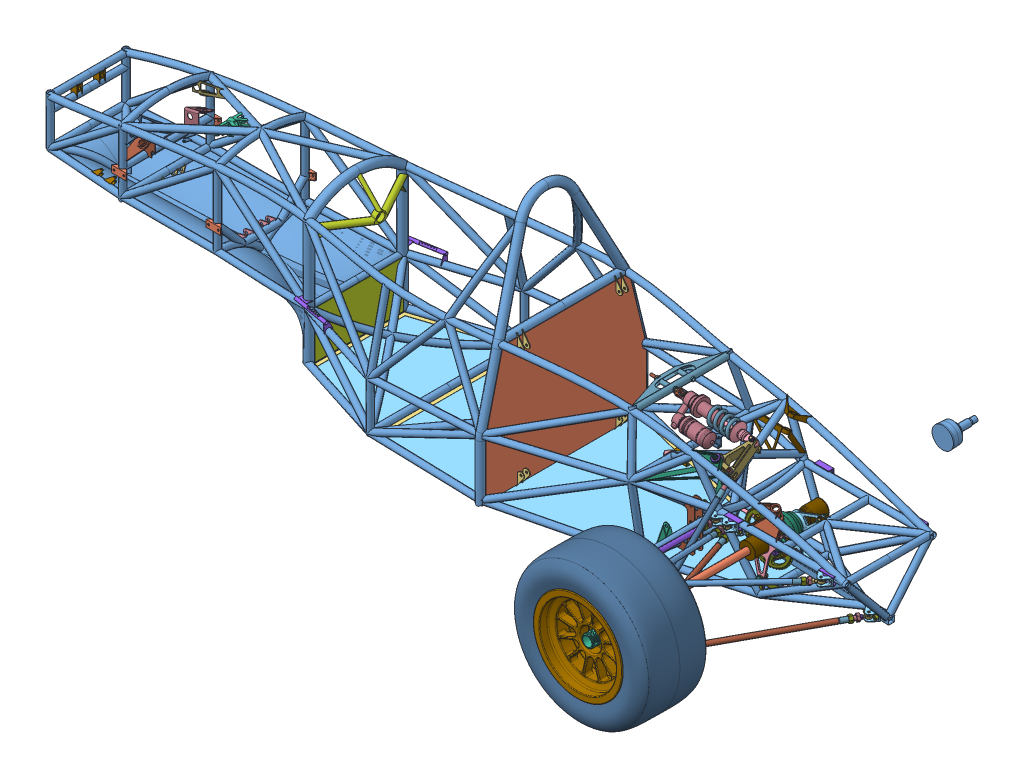
SolidWorks assembly FrameSuspensionRear, configuration Default. Lengths in mm.
Overall size (3537.14 1301.94 1659.72).
268 component instances, 104 part files, 6 mates.
Components (placement in the parent):
- ChassisTop-1: ChassisTop [Default] at origin size (3537.14 1301.94 761.25)
  - Frame-1: Frame [Default<As Machined>] at origin size (3537.14 1301.94 761.25)
  - BracketAarmMountFrontInnerUpper-1: BracketAarmMountFrontInnerUpper [Default] at (-76.9527 359.432 196.9) size (60 28 16.9)
  - BracketAarmMountFrontInnerUpper-2: BracketAarmMountFrontInnerUpper [Default] at (312.8511 359.432 196.9) size (60 28 16.9)
  - BracketAarmMountFrontInnerUpper-3: BracketAarmMountFrontInnerUpper [Default] at (-76.9527 359.432 -196.9) x (-1 0 0) z (0 0 -1) size (60 28 16.9)
  - BracketAarmMountFrontInnerUpper-4: BracketAarmMountFrontInnerUpper [Default] at (312.8511 359.432 -196.9) x (-1 0 0) z (0 0 -1) size (60 28 16.9)
  - BracketPedalMountFront-1: BracketPedalMountFront [Default] at (-76.9527 267.432 -59.5) x (0 0 -1) z (1 0 0) size (3 35 35.55)
  - BracketPedalMountFront-4: BracketPedalMountFront [Default] at (-76.9527 267.432 -28.5) x (0 0 -1) z (1 0 0) size (3 35 35.55)
  - BracketPedalMountFront-5: BracketPedalMountFront [Default] at (-76.9527 267.432 28.5) x (0 0 1) z (-1 0 0) size (3 35 35.55)
  - BracketPedalMountFront-6: BracketPedalMountFront [Default] at (-76.9527 267.432 59.5) x (0 0 1) z (-1 0 0) size (3 35 35.55)
  - BracketPedalMountRear-1: BracketPedalMountRear [Default] at (312.8511 243.432 -61) x (-1 0 0) z (0 0 1) size (41.8 36.23 3)
  - BracketPedalMountRear-2: BracketPedalMountRear [Default] at (312.8511 243.432 -32.3915) x (-1 0 0) z (0 0 1) size (41.8 36.23 3)
  - BracketPedalMountRear-3: BracketPedalMountRear [Default] at (312.8511 243.432 30) x (-1 0 0) z (0 0 1) size (41.8 36.23 3)
  - BracketPedalMountRear-4: BracketPedalMountRear [Default] at (312.8511 243.432 61) x (-0.999488 -0.031993 0) z (0 0 1) size (41.8 36.23 3)
  - BracketSteeringRack-1: BracketSteeringRack [Default] at (-122.845 359.4035 0) x (0 0 1) z (-0.731354 -0.681998 0) size (157.4 28.6 22.45)
  - Part1^ChassisTop-1: Part1^ChassisTop [Default] at origin (virtual)
  - BracketSteeringColumnBearing2-1: BracketSteeringColumnBearing2 [Default<As Machined>] at (1054.5457 325.1906 26.9611) x (0.999998 -0.002043 0.000001) z (0.000001 0.000943 1) size (68.49 50.56 124.92)
  - BracketSteeringColumnBearing3-1: BracketSteeringColumnBearing3 [Default] at (806.6109 544.4207 0) x (0 0 1) z (-0.999391 0.034899 0) size (406.05 183.54 114.99)
  - Road-1: Road [Default] at (899.7928 43.6226 57.1597) (suppressed, hidden)
  - ARB_HandleMountLeft-1: ARB_HandleMountLeft [Default] at (830.0394 301.8025 247.6998) x (-0.985348 0 -0.170553) z (0.170553 0 -0.985348) size (155.3 44.88 41.83)
  - ARB_FrontChassisTabsLeft-1: ARB_FrontChassisTabsLeft [Default<As Machined>] at (-76.9527 267.432 0) x (0 0 1) z (-1 0 0) size (38.22 15.9 83.49)
  - ARB_FrontChassisTabsRight-1: ARB_FrontChassisTabsRight [Default<As Machined>] at (-76.9527 267.432 0) x (0 0 1) z (-1 0 0) size (38.22 15.9 83.49)
  - BracketIdlerSprocket-2: BracketIdlerSprocket [Default] at (2250 187 0) x (0 0 1) z (-1 0 0) size (55.08 192.78 109.89)
    - BracketIdlerSprocket-1: BracketIdlerSprocket [Default<As Machined>] at origin size (36.02 192.78 89.01)
    - B27.7M - 3BM1-28-2: B27.7M - 3BM1-28 [B27.7M - 3BM1-28] at (112.963 9.676 43.223) x (0 0 1) z (-1 0 0) size (29.8 29.16 1.3)
    - ChainTensionerShaft-1: ChainTensionerShaft [Default] at (106.463 9.676 43.223) size (30.8 15 15)
    - Internal Tooth LW Type A-0.375-1: Internal Tooth LW Type A-0.375 [Internal Tooth LW Type A-0.375] at (123.463 9.676 43.223) x (0 -1 0) z (0 0 1) size (17.58 1.02 17.58)
    - Internal Tooth LW Type A-0.375-2: Internal Tooth LW Type A-0.375 [Internal Tooth LW Type A-0.375] at (89.463 9.676 43.223) x (0 1 0) z (0 0 1) size (17.58 1.02 17.58)
    - HX-SHCS 0.375-24x0.5x0.5-S-1: HX-SHCS 0.375-24x0.5x0.5-S [HX-SHCS 0.375-24x0.5x0.5-S] at (78.922 9.676 43.223) size (22.23 14.29 14.29)
    - HX-SHCS 0.375-24x0.5x0.5-S-2: HX-SHCS 0.375-24x0.5x0.5-S [HX-SHCS 0.375-24x0.5x0.5-S] at (134.004 9.676 43.223) x (-1 0 0) z (0 0.924225 0.381849) size (22.23 14.29 14.29)
    - B27.7M - 3BM1-28-3: B27.7M - 3BM1-28 [B27.7M - 3BM1-28] at (98.663 9.676 43.223) x (0 -0.075373 0.997155) z (-1 0 0) size (29.8 29.16 1.3)
    - 40-0.5P1ST12T12SB3.0H.75L1.0000N-3: 40-0.5P1ST12T12SB3.0H.75L1.0000N [40-0.5P1ST12T12SB3.0H.75L1.0000N] at (102.7792 9.676 43.223) x (1 0 0) z (0 0.511924 0.859031) size (19.05 53.51 53.51)
    - SKF - NA 4902 - 18,SI,NC,18-2: SKF - NA 4902 - 18,SI,NC,18 [SKF - NA 4902 - 18,SI,NC,18] at (106.463 9.676 43.223) size (13 28 28)
  - BracketDifferentialTop-1: BracketDifferentialTop [Default] at (2640 369 -19.137) size (35.79 30.2 3.06)
  - BracketDifferentialTop-2: BracketDifferentialTop [Default] at (2640 369 -3.437) size (35.79 30.2 3.06)
  - BracketDifferentialTop-3: BracketDifferentialTop [Default] at (2640 369 144.169) size (35.79 30.2 3.06)
  - BracketDifferentialTop-4: BracketDifferentialTop [Default] at (2640 369 128.469) size (35.79 30.2 3.06)
  - BracketDifferentialBottom2-1: BracketDifferentialBottom2 [Default] at (2514.3722 202.1336 -16.1675) x (-0.999056 0.043437 -0.000036) z (0 -0.000823 -1) size (30.06 50.08 6.47)
  - BracketDifferentialBottom-2: BracketDifferentialBottom [Default] at (2514.3722 202.1441 -3.4675) x (0.999056 -0.043437 0.000036) z (0 0.000823 1) size (30 24.68 3)
  - BracketEngineMountFront-1: BracketEngineMountFront [Default] at (1550 77.8 197.06) x (-0.707101 -0.707113 0) z (0 0 1) size (59.7 40.23 3)
  - BracketEngineMountFront-5: BracketEngineMountFront [Default] at (1550 77.8 174.06) x (-0.707101 -0.707113 0) z (0 0 1) size (59.7 40.23 3)
  - BracketEngineMountFront-6: BracketEngineMountFront [Default] at (1550 77.8 -207.212) x (-0.707101 -0.707113 0) z (0 0 1) size (59.7 40.23 3)
  - BracketEngineMountFront-7: BracketEngineMountFront [Default] at (1550 77.8 -230.212) x (-0.707101 -0.707113 0) z (0 0 1) size (59.7 40.23 3)
  - BracketEngineMountLeftRearUpper-1: BracketEngineMountLeftRearUpper [Default] at (2083.8 369 68.1) x (0.872737 0.488191 0) z (0 0 1) size (49.37 31.4 38.96)
  - BracketEngineMountRightRearUpper-1: BracketEngineMountRightRearUpper [Default] at (2083.8 369 -91.775) x (0.872737 0.488191 0) z (0 0 1) size (49.37 31.4 38.96)
  - BracketEngineMountLeftRearLower-1: BracketEngineMountLeftRearLower [Default] at (2083.8 73 83.364) x (0 0 1) z (-1 0 0) size (48.92 61.08 44.76)
  - BracketEngineMountRightRearLower-1: BracketEngineMountRightRearLower [Default] at (2083.8 73 -73.511) x (0 0 1) z (-1 0 0) size (48.92 61.08 44.76)
  - BracketAarmMountRearUpper-1: BracketAarmMountRearUpper [Default] at (2445.5428 369 196.912) size (60 31.4 21.97)
  - BracketAarmMountRearUpper-2: BracketAarmMountRearUpper [Default] at (2835.3458 369 197.2126) size (60 31.4 21.97)
  - BracketAarmMountRearUpper-3: BracketAarmMountRearUpper [Default] at (2445.5428 369 -197.2126) x (1 0 0) z (0 0 -1) size (60 31.4 21.97)
  - BracketAarmMountRearUpper-4: BracketAarmMountRearUpper [Default] at (2835.3458 369 -197.2126) x (1 0 0) z (0 0 -1) size (60 31.4 21.97)
  - BracketShockMountFront-1: BracketShockMountFront [Default] at (-400 452.432 -46.6) x (0 0 1) z (-1 0 0) size (23.2 50 25.43)
  - BracketShockMountFront-2: BracketShockMountFront [Default] at (-400 452.432 46.6) x (0 0 1) z (-1 0 0) size (23.2 50 25.43)
  - SuspensionRockerMountLeftFrontUpper-1: SuspensionRockerMountLeftFrontUpper [Default<As Machined>] at (-4.1616 10 0) size (144.63 102.27 61.32)
  - SuspensionRockerMountLeftFrontLower-1: SuspensionRockerMountLeftFrontLower [Default<As Machined>] at (-4.1616 10 0) size (58.7 81.5 92.95)
  - SuspensionRockerMountRightFrontUpper-1: SuspensionRockerMountRightFrontUpper [Default<As Machined>] at (-4.1616 10 0) size (144.63 102.27 61.32)
  - SuspensionRockerMountRightFrontLower-1: SuspensionRockerMountRightFrontLower [Default<As Machined>] at (-4.1616 10 0) size (58.7 81.5 92.95)
  - ShockXMember2-1: ShockXMember2 [Default] at origin size (79.41 25.4 400)
  - SuspensionRockerMountLeftRear2-1: SuspensionRockerMountLeftRear2 [Default<As Machined>] at origin size (294.24 185.3 177.85)
  - BracketFrameDiffLeftRearLower^ChassisTop-1: BracketFrameDiffLeftRearLower^ChassisTop [Default] at origin size (95.94 48.5 3) (virtual)
  - BracketFrameDiffLeftRearLowerInside^ChassisTop-1: BracketFrameDiffLeftRearLowerInside^ChassisTop [Default] at origin size (67.39 68.06 3.53) (virtual)
  - SuspensionRockerMountRightRear2-1: SuspensionRockerMountRightRear2 [Default<As Machined>] at origin size (294.24 185.3 177.85)
  - SkinMountMainRollBulkhead-1: SkinMountMainRollBulkhead [Default] at origin size (1.04 520.21 661.74)
  - BracketEngineMountFront-8: BracketEngineMountFront [Default] at (1550 598 174.06) x (-0.707113 0.707101 0) z (0 0 1) size (59.7 40.23 3)
  - BracketEngineMountFront-9: BracketEngineMountFront [Default] at (1550 598 197.06) x (-0.707113 0.707101 0) z (0 0 1) size (59.7 40.23 3)
  - BracketEngineMountFront-10: BracketEngineMountFront [Default] at (1550 598 -230.212) x (-0.707113 0.707101 0) z (0 0 1) size (59.7 40.23 3)
  - BracketEngineMountFront-11: BracketEngineMountFront [Default] at (1550 598 -207.212) x (-0.707113 0.707101 0) z (0 0 1) size (59.7 40.23 3)
  - SkinMainRollBulkhead-1: SkinMainRollBulkhead [Default] at (1 0 0) size (1.01 525.01 661.73)
  - SkinMountFloorFront-1: SkinMountFloorFront [Default] at origin size (1380.8 1 661.73)
  - SkinMountFloorRear-1: SkinMountFloorRear [Default] at origin size (428.76 53.46 400)
  - SkinFloorMain-1: SkinFloorMain [Default] at origin size (1811.18 53.27 661.66)
  - SkinMountFrontRollBulkhead-1: SkinMountFrontRollBulkhead [Default] at origin size (1 194.43 370.44)
  - SkinFrontRollBulkhead-1: SkinFrontRollBulkhead [Default] at origin size (0.61 194.43 370.44)
  - ARB_HandleMountRight-1: ARB_HandleMountRight [Default] at (830.1032 301.8025 -247.5528) x (-0.985545 0 0.169414) z (0.169414 0 0.985545) size (155.3 44.88 41.83)
  - BracketARB_RearLeft-1: BracketARB_RearLeft [Default] at origin size (53.73 35.4 34.54)
  - BracketARB_RearRight-1: BracketARB_RearRight [Default] at origin size (53.73 35.4 34.54)
- SuspensionLR4-1: SuspensionLR4 [Default] at (2851.1738 170.1686 0) x (0 0 -1) z (1 0 0) size (932.8 601.59 929.55)
  - ControlArmLFLower-1: ControlArmLFLower [Default] at (-710.12 6.8929 -344.6219) x (1 0 0) z (0 -0.043844 0.999038) size (715.96 52.66 603.91)
    - ControlArmLFL-1: ControlArmLFL [Default] at origin size (613.02 44.71 511.54)
    - RodEndRace375-1: RodEndRace375 [Default] at (675.42 0 -219.4573) x (-0.293449 0.313398 -0.903144) z (-0.096845 -0.949622 -0.298059) size (25.4 72.71 20.2)
    - RodEndRace375-2: RodEndRace375 [Default] at (675.42 0 344.1437) x (0.452303 0.086149 -0.887694) z (0.039111 -0.996282 -0.076759) size (25.4 72.71 20.2)
    - RodEndAdjuster375-1: RodEndAdjuster375 [Default] at (614.5714 0 -199.6864) x (0.275322 -0.454081 0.847354) z (0.140319 0.89096 0.431857) size (27.49 36.1 23.81)
    - RodEndAdjuster375-2: RodEndAdjuster375 [Default] at (618.4134 0 315.0974) x (-0.195306 -0.902734 0.38331) z (-0.409833 0.430198 0.804342) size (27.49 36.1 23.81)
    - ControlArmEnd-1: ControlArmEnd [Default] at (620.817 0 -201.7157) x (-0.302942 0.197314 -0.932359) z (0.060973 0.98034 0.187657) size (19.05 40 19.05)
    - ControlArmEnd-2: ControlArmEnd [Default] at (618.9975 0 315.395) x (0.360664 0.607355 -0.707843) z (-0.275733 0.794431 0.541157) size (19.05 40 19.05)
    - SphericalBeaingRace625-1: SphericalBeaingRace625 [Default] x (-0.318509 0 0.94792) z (0 -1 0) size (30.17 30.17 12.7)
    - HNUT 0.6250-18-D-N-2: HNUT 0.6250-18-D-N [HNUT 0.6250-18-D-N] at (634.3207 0 -206.1033) x (0.201042 -0.759433 0.618743) z (0.951057 0 -0.309017) size (23.83 27.51 14.2)
    - HNUT 0.6250-18-D-N-3: HNUT 0.6250-18-D-N [HNUT 0.6250-18-D-N] at (631.6485 0 321.841) x (0.438064 0.262546 -0.85975) z (0.891007 0 0.45399) size (23.83 27.51 14.2)
    - HNUT 0.3750-24-D-N-5: HNUT 0.3750-24-D-N [HNUT 0.3750-24-D-N] at (657.0454 0 -213.487) x (0.208644 -0.737646 0.642141) z (0.951057 0 -0.309017) size (14.27 16.48 8.56)
    - HNUT 0.3750-24-D-N-6: HNUT 0.3750-24-D-N [HNUT 0.3750-24-D-N] at (658.2056 0 335.3725) x (0.45399 0 -0.891007) z (0.891007 0 0.45399) size (14.27 16.48 8.56)
    - RodEndBall375-1: RodEndBall375 [Default] at (675.42 0 344.1437) x (0.94832 0.017594 -0.316829) z (-0.01605 0.999843 0.007482) size (17.45 17.45 22.2)
    - RodEndBall375-2: RodEndBall375 [Default] at (675.42 0 -219.4573) x (0.987569 -0.05525 -0.147157) z (0.094991 0.955677 0.278674) size (17.45 17.45 22.2)
  - ControlArmLFUpper-1: ControlArmLFUpper [Default] at (-675.4646 264.0882 -321.2938) x (0.990081 -0.1405 0) z (0 0 1) size (505.57 33.91 426.53)
    - ControlArmLFU-1: ControlArmLFU [Default] at origin size (412.95 24.33 343.13)
    - RodEndRace375-1: RodEndRace375 [Default] at (464.46 0 -84.3372) x (0.178525 -0.038809 0.98317) z (0.006934 0.999247 0.038184) size (25.4 72.71 20.2)
    - RodEndRace375-2: RodEndRace375 [Default] at (464.46 0 305.4662) x (0.549455 0.011461 -0.835444) z (0.006298 -0.999934 -0.009575) size (25.4 72.71 20.2)
    - RodEndAdjuster375-1: RodEndAdjuster375 [Default] at (399.4235 0 -72.5278) x (0.060172 -0.941577 0.331378) z (0.168222 0.336797 0.926428) size (27.49 36.1 23.81)
    - RodEndAdjuster375-2: RodEndAdjuster375 [Default] at (409.2335 0 269.1448) x (-0.120313 -0.975735 0.182935) z (-0.536158 0.218953 0.815226) size (27.49 36.1 23.81)
    - ControlArmEnd-1: ControlArmEnd [Default] at (404.8301 0 -73.5095) x (-0.175147 0.197314 -0.964568) z (0.035252 0.98034 0.194139) size (19.05 40 19.05)
    - ControlArmEnd-2: ControlArmEnd [Default] at (413.8246 0 272.1643) x (0.436533 0.607355 -0.663746) z (-0.333736 0.794431 0.507444) size (19.05 40 19.05)
    - SphericalBeaingRace625-1: SphericalBeaingRace625 [Default] x (-0.305969 0 0.952042) z (0 -1 0) size (30.17 30.17 12.7)
    - RodEndBall375-1: RodEndBall375 [Default] at (464.46 0 -84.3372) x (0.999394 -0.030484 -0.016803) z (-0.030212 -0.999412 0.016234) size (17.45 17.45 22.2)
    - RodEndBall375-2: RodEndBall375 [Default] at (464.46 0 305.4662) x (0.9994 0.031332 -0.014778) z (0.031419 -0.99949 0.005714) size (17.45 17.45 22.2)
    - SphericalBearingBall625-1: SphericalBearingBall625 [Default] x (0.993683 -0.021796 -0.110086) z (0.010929 0.99509 -0.098368) size (26 32.6 22.58)
    - HNUT 0.3750-16-D-N-5: HNUT 0.3750-16-D-N [HNUT 0.3750-16-D-N] at (443.3648 0 -80.5067) x (-0.17866 0 -0.983911) z (0.983911 0 -0.17866) size (14.27 16.48 8.56)
    - HNUT 0.3750-16-D-N-6: HNUT 0.3750-16-D-N [HNUT 0.3750-16-D-N] at (446.5467 0 293.685) x (0.549492 0 -0.835499) z (0.835499 0 0.549492) size (14.27 16.48 8.56)
    - HNUT 0.6250-18-D-N-3: HNUT 0.6250-18-D-N [HNUT 0.6250-18-D-N] at (425.6875 0 279.9663) x (0.549492 0 -0.835499) z (0.835499 0 0.549492) size (23.83 27.51 14.2)
    - HNUT 0.6250-18-D-N-4: HNUT 0.6250-18-D-N [HNUT 0.6250-18-D-N] at (418.8002 0 -76.0462) x (-0.17866 0 -0.983911) z (0.983911 0 -0.17866) size (23.83 27.51 14.2)
  - UprighntLR1-1: UprighntLR1 [Default] at (-759.1719 137.3299 -341.5119) x (0.000404 0.023987 -0.999712) z (0.999954 -0.009551 0.000174) size (137.2 292.52 82.5)
  - SteeringArmLeftRear-1: SteeringArmLeftRear [Default] at (-706.7664 262.3003 -295.98) x (0.000404 0.023987 -0.999712) z (0.999954 -0.009551 0.000174) size (117.16 36.34 48.84)
  - AxleFront-1: AxleFront [Default] at (-763.3542 137.3698 -341.5127) x (0.999954 -0.009551 0.000174) z (0.006778 0.722254 0.691594) size (185.85 156 156)
  - BearingWheelCivicFront-1: BearingWheelCivicFront [Default] at (-697.3572 136.7395 -341.5011) x (0.00307 0.338652 0.940907) z (-0.999954 0.009551 -0.000174) size (73 73 55.34)
  - TierodF-2: TierodF [Default] at (-675.8742 259.4631 -398.4651) x (-0.118174 -0.028476 -0.992585) z (0.125564 0.991136 -0.043383) size (36.06 503.39 35.02)
    - RodEndRace375-1: RodEndRace375 [Default] at origin size (25.4 72.71 20.2)
    - RodEndRace375-2: RodEndRace375 [Default] at (0 -467.261 0) x (-1 0 0) z (0 0 1) size (25.4 72.71 20.2)
    - RodEndAdjuster375-2: RodEndAdjuster375 [Default] at (0 -400.5317 0) x (-0.834309 0 -0.551296) z (-0.551296 0 0.834309) size (27.49 36.1 23.81)
    - ControlArmEnd-2: ControlArmEnd [Default] at (0 -403.3749 0) x (0.999448 0 0.03323) z (-0.03323 0 0.999448) size (19.05 40 19.05)
    - TierodTubeF-1: TierodTubeF [Default] at origin size (19.05 335.97 19.05)
    - TieRodEnd375-750-1: TieRodEnd375-750 [Default] at (0 -53.1072 0) x (0.980988 0 -0.19407) z (0.19407 0 0.980988) size (19.05 19.05 19.05)
    - HNUT 0.6250-18-D-N-1: HNUT 0.6250-18-D-N [HNUT 0.6250-18-D-N] at (0 -403.3749 0) x (1 0 0) z (0 1 0) size (23.83 27.51 14.2)
    - HNUT 0.3750-24-D-N-2: HNUT 0.3750-24-D-N [HNUT 0.3750-24-D-N] at (0 -445.1915 0) x (1 0 0) z (0 -1 0) size (14.27 16.48 8.56)
    - HNUT 0.3750-24-D-N-3: HNUT 0.3750-24-D-N [HNUT 0.3750-24-D-N] at (0 -25.4974 0) x (1 0 0) z (0 1 0) size (14.27 16.48 8.56)
  - RodEndBall375-1: RodEndBall375 [Default] at (-675.8742 259.4631 -398.4651) x (0.998859 -0.008408 -0.047012) z (0.009544 0.999667 0.02399) size (17.45 17.45 22.2)
  - RoadSurface-1: RoadSurface [Default] at (-31.5379 -149.5744 131.1439) (suppressed, hidden)
  - PushRodRear-2: PushRodRear [Default] at (-682.6744 14.2273 -342.0617) x (0.120174 0.167217 0.978569) z (0.513162 -0.854273 0.082958) size (39.98 648.94 31.36) (flexible)
    - RodEndRace375-1: RodEndRace375 [Default] at (1.7755 -13.8832 -8.6862) x (0.994588 0.020332 0.101893) z (-0.101913 -0.000053 0.994793) size (25.4 72.71 20.2)
    - RodEndRace375-2: RodEndRace375 [Default] at (14.1658 -626.1943 -7.4495) x (-0.108826 -0.00421 -0.994052) z (-0.993855 -0.019891 0.108889) size (25.4 72.71 20.2)
    - RodEndAdjuster375-2: RodEndAdjuster375 [Default] at (12.8393 -560.6405 -7.5819) x (0.177643 0.001607 -0.984094) z (-0.983887 -0.020268 -0.177639) size (27.49 36.1 23.81)
    - ControlArmEnd-2: ControlArmEnd [Default] at (13.0347 -570.2981 -7.5624) x (0.999642 0.020263 0.017454) z (-0.017492 0.001665 0.999846) size (19.05 40 19.05)
    - TieRodEnd375-750-1: TieRodEnd375-750 [Default] at (2.8321 -66.1024 -8.5808) x (0.980545 0.019447 -0.19533) z (0.19525 0.005932 0.980736) size (19.05 19.05 19.05)
    - PushRodTubeRear-1: PushRodTubeRear [Default] at (1.8747 -18.7847 -8.6763) x (0.999795 0.020229 -0.001285) z (0.001244 0.002045 0.999997) size (19.05 484 19.05)
    - HNUT 0.2500-28-D-N-1: HNUT 0.2500-28-D-N [HNUT 0.2500-28-D-N] at (13.0347 -570.2981 -7.5624) x (0.996272 0.020329 0.083833) z (-0.020231 0.999793 -0.002019) size (11.11 12.83 5.74)
    - HNUT 0.3750-24-D-N-2: HNUT 0.3750-24-D-N [HNUT 0.3750-24-D-N] at (13.7428 -605.2911 -7.4918) x (0.999767 0.020246 0.007429) z (0.020231 -0.999793 0.002019) size (14.27 16.48 8.56)
    - HNUT 0.3750-24-D-N-3: HNUT 0.3750-24-D-N [HNUT 0.3750-24-D-N] at (2.2736 -38.4983 -8.6365) x (0.999795 0.020229 -0.001285) z (-0.020231 0.999793 -0.002019) size (14.27 16.48 8.56)
  - SuspensionRockerLeftRearAssy-2: SuspensionRockerLeftRearAssy [Default] at (-15.678 -26.7976 -191.9587) x (0.998024 0.012634 0.061557) z (-0.056792 -0.237976 0.969609) size (167.13 138.17 106.24)
    - SuspensionRockerRear-1: SuspensionRockerRear [Default] at origin size (144.34 107.74 99.29)
    - SKFNNF5004ADB-2LSV-1: SKFNNF5004ADB-2LSV [Default] at (-142.9181 282.5756 -383.7443) x (0.736283 0.294495 -0.609229) z (0.479372 -0.862446 0.162447) size (42 42 30)
    - B27.7M - 3BM1-42-2: B27.7M - 3BM1-42 [B27.7M - 3BM1-42] at (-150.1087 295.5123 -386.181) x (0.802316 0.355657 -0.479372) z (0.479372 -0.862446 0.162447) size (44.5 43.63 1.6)
    - B27.7M - 3BM1-42-3: B27.7M - 3BM1-42 [B27.7M - 3BM1-42] at (-135.7275 269.6389 -381.3076) x (0.725632 0.49362 0.479372) z (-0.479372 0.862446 -0.162447) size (44.5 43.63 1.6)
    - RockerArmShaft-1: RockerArmShaft [Default] at (-142.9181 282.5756 -383.7443) x (0.479372 -0.862446 0.162447) z (0.506446 0.423023 0.751374) size (64 20 20)
    - RockerArmSpacer-1: RockerArmSpacer [Default] at (-152.2659 299.3933 -386.912) x (0.773342 0.327609 -0.542784) z (0.479372 -0.862446 0.162447) size (30 30 4.5)
    - RockerArmSpacer-2: RockerArmSpacer [Default] at (-135.7275 269.6389 -381.3076) x (0.802316 0.355657 -0.479372) z (0.479372 -0.862446 0.162447) size (30 30 4.5)
    - RockerArmShaftWasher-1: RockerArmShaftWasher [Default] at (-159.6961 312.7612 -389.43) x (0.792064 0.345455 -0.503285) z (0.479372 -0.862446 0.162447) size (30 30 3)
    - RockerArmShaftWasher-2: RockerArmShaftWasher [Default] at (-127.5782 254.9773 -378.546) x (0.802316 0.355657 -0.479372) z (0.479372 -0.862446 0.162447) size (30 30 3)
    - Regular LW 0.375-5: Regular LW 0.375 [Regular LW 0.375] at (-159.6961 312.7612 -389.43) x (0.479372 -0.862446 0.162447) z (-0.162447 0.094704 0.982162) size (2.39 17.35 17.32)
    - Regular LW 0.375-6: Regular LW 0.375 [Regular LW 0.375] at (-126.1401 252.39 -378.0587) x (-0.479372 0.862446 -0.162447) z (0.162447 0.269102 0.949313) size (2.39 17.35 17.32)
    - Regular LW 0.375-7: Regular LW 0.375 [Regular LW 0.375] at (-139.2214 275.4614 -321.6177) x (-0.479372 0.862446 -0.162447) z (0.162447 0.269102 0.949313) size (2.39 17.35 17.32)
    - Regular LW 0.375-8: Regular LW 0.375 [Regular LW 0.375] at (-55.612 359.8738 -356.4996) x (-0.479372 0.862446 -0.162447) z (0.72282 0.492977 0.484257) size (2.39 17.35 17.32)
    - HX-SHCS 0.375-24x0.5x0.5-S-1: HX-SHCS 0.375-24x0.5x0.5-S [HX-SHCS 0.375-24x0.5x0.5-S] at (-165.4067 323.0352 -391.3651) x (0.479372 -0.862446 0.162447) z (0.183698 0.279607 0.942377) size (22.23 14.29 14.29)
    - HX-SHCS 0.375-24x0.5x0.5-S-2: HX-SHCS 0.375-24x0.5x0.5-S [HX-SHCS 0.375-24x0.5x0.5-S] at (-120.4295 242.116 -376.1235) x (-0.479372 0.862446 -0.162447) z (0.162447 0.269102 0.949313) size (22.23 14.29 14.29)
    - Preferred Narrow FW 0.375-2: Preferred Narrow FW 0.375 [Preferred Narrow FW 0.375] at (-156.4788 306.5095 -327.4658) x (0.479372 -0.862446 0.162447) z (-0.162447 0.094704 0.982162) size (1.65 20.62 20.62)
    - HX-SHCS 0.375-24x1.625x1.625-S-4: HX-SHCS 0.375-24x1.625x1.625-S [HX-SHCS 0.375-24x1.625x1.625-S] at (-161.8362 316.1482 -329.2813) x (0.479372 -0.862446 0.162447) z (-0.162447 0.094704 0.982162) size (50.8 14.29 14.29)
    - HNUT 0.3750-24-D-N-1: HNUT 0.3750-24-D-N [HNUT 0.3750-24-D-N] at (-133.9735 266.0199 -319.8393) x (0.802316 0.355657 -0.479372) z (0.479372 -0.862446 0.162447) size (14.27 16.48 8.56)
    - HNUT 0.3750-24-D-N-2: HNUT 0.3750-24-D-N [HNUT 0.3750-24-D-N] at (-55.612 359.8738 -356.4996) x (0.858951 0.423104 -0.288419) z (0.479372 -0.862446 0.162447) size (14.27 16.48 8.56)
    - ARB_RockerArmShaftFront-1: ARB_RockerArmShaftFront [Default] at (-37.21 326.7666 -350.2636) x (-0.479372 0.862446 -0.162447) z (0.409805 0.383658 0.827567) size (79.78 20 20)
  - ShockInner-1: ShockInner [Default] at (-50.5751 389.1023 -456.1842) x (0.836245 0.545292 0.057878) z (-0.54677 0.83719 0.012447) size (68.48 147.08 68.48)
  - SuspAttachInnerFront-1: SuspAttachInnerFront [Default] at (-34.7 16.5148 -563.8681) x (0 0.043844 -0.999038) z (0 0.999038 0.043844) size (60 31.4 28)
  - SuspAttachInnerFront-2: SuspAttachInnerFront [Default] at (-34.7 -8.1959 -0.8091) x (0 0.043844 -0.999038) z (0 0.999038 0.043844) size (60 31.4 28)
  - SuspAttachInnerFront-3: SuspAttachInnerFront [Default] at (-215.6118 198.8314 -405.631) x (0 0 1) z (0 -1 0) size (60 31.4 28)
  - SuspAttachInnerFront-4: SuspAttachInnerFront [Default] at (-215.6118 198.8314 -15.8276) x (0 0 1) z (0 -1 0) size (60 31.4 28)
  - AarmMountInner-2: AarmMountInner [Default] at (0 17.3917 -583.8488) x (0 -0.166883 0.985977) z (-1 0 0) size (18 18 32)
  - SHCS 0.375-16x1x1-C-5: SHCS 0.375-16x1x1-C [SHCS 0.375-16x1x1-C] at (-30.9126 17.3917 -583.8488) size (34.92 14.29 14.29)
  - SHCS 0.375-16x1x1-C-6: SHCS 0.375-16x1x1-C [SHCS 0.375-16x1x1-C] at (-30.9126 15.6379 -543.8873) x (1 0 0) z (0 0.602433 0.798169) size (34.92 14.29 14.29)
  - SHCS 0.375-16x1x1-C-7: SHCS 0.375-16x1x1-C [SHCS 0.375-16x1x1-C] at (-30.9126 -7.319 -20.7899) size (34.92 14.29 14.29)
  - SHCS 0.375-16x1x1-C-8: SHCS 0.375-16x1x1-C [SHCS 0.375-16x1x1-C] at (-30.9126 -9.0728 19.1717) x (1 0 0) z (0 -0.470742 -0.882271) size (34.92 14.29 14.29)
  - LS 0.375-5: LS 0.375 [LS 0.375] at (-19 17.3917 -583.8488) x (1 0 0) z (0 -0.6623 0.749238) size (2.39 17.27 17.25)
  - LS 0.375-6: LS 0.375 [LS 0.375] at (-19 15.6379 -543.8873) size (2.39 17.27 17.25)
  - LS 0.375-7: LS 0.375 [LS 0.375] at (-19 -9.0728 19.1717) size (2.39 17.27 17.25)
  - LS 0.375-8: LS 0.375 [LS 0.375] at (-19 -7.319 -20.7899) size (2.39 17.27 17.25)
  - AarmMountInner-3: AarmMountInner [Default] at (0 15.6379 -543.8873) x (0 -0.167006 0.985956) z (-1 0 0) size (18 18 32)
  - AarmMountInner-4: AarmMountInner [Default] at (0 -9.0728 19.1717) x (0 -0.610876 -0.791727) z (-1 0 0) size (18 18 32)
  - AarmMountInner-5: AarmMountInner [Default] at (0 -7.319 -20.7899) x (0 -0.167006 0.985956) z (-1 0 0) size (18 18 32)
  - WheelRear1-1: WheelRear1 [Default] at (-763.3542 137.3698 -341.5127) x (-0.001674 -0.157219 0.987562) z (-0.999954 0.009551 -0.000174) size (367.66 367.66 268.71)
  - TireRear-1: TireRear [Default] at (-758.7994 137.3263 -341.5119) x (0.009551 0.999953 -0.001494) z (-0.999954 0.009551 -0.000174) size (576.57 576.57 310.41)
  - ShockClevisRear-1: ShockClevisRear [Default] at (-37.5462 402.5332 -782.1551) x (-0.015475 -0.028391 0.999477) z (0.886168 0.462584 0.02686) size (149.99 28.71 30)
  - Internal Tooth LW Type A-0.375-2: Internal Tooth LW Type A-0.375 [Internal Tooth LW Type A-0.375] at (-37.4137 402.7763 -790.7104) x (0.992912 0.117367 0.018707) z (-0.117837 0.992683 0.026373) size (17.58 1.02 17.58)
  - Internal Tooth LW Type A-0.375-3: Internal Tooth LW Type A-0.375 [Internal Tooth LW Type A-0.375] at (-36.2402 404.9292 -866.5047) x (0.943611 -0.331014 0.005207) z (-0.330693 -0.943199 -0.031912) size (17.58 1.02 17.58)
  - Preferred Narrow FW 0.375-1: Preferred Narrow FW 0.375 [Preferred Narrow FW 0.375] at (-36.256 404.9004 -865.4893) x (0.015475 0.028391 -0.999477) z (0.889277 -0.457368 0.000777) size (1.65 20.62 20.62)
  - Preferred Narrow FW 0.375-2: Preferred Narrow FW 0.375 [Preferred Narrow FW 0.375] at (-37.398 402.8051 -791.7259) x (-0.015475 -0.028391 0.999477) z (0.763167 -0.646168 -0.006539) size (1.65 20.62 20.62)
  - Preferred Narrow FW 0.375-3: Preferred Narrow FW 0.375 [Preferred Narrow FW 0.375] at (-44.1385 413.8713 -759.9236) x (0.463105 -0.886121 -0.018001) z (0.780251 0.397973 0.48252) size (1.65 20.62 20.62)
  - Regular LW 0.375-1: Regular LW 0.375 [Regular LW 0.375] at (-31.6347 389.946 -760.4096) x (-0.463105 0.886121 0.018001) z (-0.39417 -0.224107 0.891294) size (2.39 17.35 17.32)
  - HX-SHCS 0.375-24x1.625x1.625-S-1: HX-SHCS 0.375-24x1.625x1.625-S [HX-SHCS 0.375-24x1.625x1.625-S] at (-49.3142 423.7746 -759.7224) x (0.463105 -0.886121 -0.018001) z (0.533654 0.262568 0.80391) size (50.8 14.29 14.29)
  - Hex Nut_AI-1: Hex Nut_AI [HNUT 0.3750-24-D-N] at (-37.5462 402.5332 -782.1551) x (0.531517 -0.8469 -0.015827) z (-0.015475 -0.028391 0.999477) size (14.27 16.48 8.56)
  - Hex Nut_AI-2: Hex Nut_AI [HNUT 0.3750-24-D-N] at (-36.1078 405.1723 -875.0601) x (0.851536 0.523545 0.028056) z (0.015475 0.028391 -0.999477) size (14.27 16.48 8.56)
  - Hex Nut_AI-3: Hex Nut_AI [HNUT 0.3750-24-D-N] at (-26.5649 380.2453 -760.6066) x (0.79719 0.425332 -0.428464) z (0.463105 -0.886121 -0.018001) size (14.27 16.48 8.56)
  - ShockOuter-2: ShockOuter [Default] at (-37.8866 401.9086 -760.1666) x (-0.885323 -0.461543 -0.056398) z (0.463105 -0.886121 -0.018001) size (134.3 211.65 68.6)
  - Spring68x12-2: Spring68x12 [Default] at (-47.8333 391.8696 -521.871) x (0.995395 0.084575 0.045112) z (-0.086324 0.995529 0.038337) size (71.27 164.23 68.78)
  - SuspAttachInnerFront-5: SuspAttachInnerFront [Default] at (-215.6118 198.8314 -451.523) x (0 0 1) z (0 -1 0) size (60 31.4 28)
  - RockerArmSpacer-1: RockerArmSpacer [Default] at (-153.7227 354.1219 -505.5926) x (0.761644 0.42124 0.492398) z (-0.492398 0.8702 0.017198) size (30 30 4.5)
- AxleRear-1: AxleRear [Default] at (2512.5 306.7507 -34.4819) x (0 0 -1) z (1 0 0) size (1474.27 283.26 283.32)
  - DifferentialHonda-1: DifferentialHonda [Default] at (-112.1 0 0) size (135.8 130.78 136.49)
  - Sprocket50-1: Sprocket50 [Default] at (-145.6668 0 0) x (0 0.587785 -0.809017) z (1 0 0) size (202.93 202.69 9.7)
  - Sprocket2DifferentialAdapter-1: Sprocket2DifferentialAdapter [Default] at (-120.1368 0 0) x (0 0 1) z (-1 0 0) size (158.36 152.5 16.04)
  - CVjointCivicInner-1: CVjointCivicInner [Default] at (-231.2356 0 0) x (1 0 0) z (0 0.088755 0.996053) size (136.25 65.07 65.07)
  - CVjointCivicInner-2: CVjointCivicInner [Default] at (73.8356 0 0) x (-1 0 0) z (0 -0.942827 -0.333282) size (136.25 65.07 65.07)
  - CVjointCivicOuter-1: CVjointCivicOuter [Default] at (-631.2356 0 0) x (-1 0 0) z (0 -0.803564 -0.595218) size (134.6 88 88)
  - CVjointCivicOuter-2: CVjointCivicOuter [Default] at (573.8356 0 0) size (134.6 88 88)
  - AxleLeftRear-1: AxleLeftRear [Default] at (-431.2356 0 0) x (1 0 0) z (0 -0.020032 0.999799) size (400 27 27)
  - B27.7M - 3BM1-55-1: B27.7M - 3BM1-55 [B27.7M - 3BM1-55] at (-35.4 0 0) x (0 0.02748 -0.999622) z (1 0 0) size (58.4 57.21 2)
  - B27.7M - 3BM1-55-2: B27.7M - 3BM1-55 [B27.7M - 3BM1-55] at (-126.7 0 0) x (0 0.383049 0.923728) z (1 0 0) size (58.4 57.21 2)
  - DifferentialSupportLeft-1: DifferentialSupportLeft [Default] at (-124.85 0 0) x (0 0 1) z (-1 0 0) size (152.97 210.81 51)
  - DifferentialSupportRight-1: DifferentialSupportRight [Default] at (-15.2 0 0) x (0 0 1) z (-1 0 0) size (147.58 188.62 26)
  - Regular LW 0.375-1: Regular LW 0.375 [Regular LW 0.375] at (-161.1134 62.2 102.6) x (1 0 0) z (0 -0.652254 0.758001) size (2.39 17.35 17.32)
  - Regular LW 0.375-2: Regular LW 0.375 [Regular LW 0.375] at (-34.549 62.2 102.6) x (1 0 0) z (0 -0.033927 0.999424) size (2.39 17.35 17.32)
  - Preferred Narrow FW 0.375-1: Preferred Narrow FW 0.375 [Preferred Narrow FW 0.375] at (-14.2 62.2 102.6) x (1 0 0) z (0 -0.691831 0.722059) size (1.65 20.62 20.62)
  - Preferred Narrow FW 0.375-2: Preferred Narrow FW 0.375 [Preferred Narrow FW 0.375] at (-183.85 62.2 102.6) x (-1 0 0) z (0 0.544943 0.838473) size (1.65 20.62 20.62)
  - HX-SHCS 0.375-24x1.25x1.25-S-3: HX-SHCS 0.375-24x1.25x1.25-S [HX-SHCS 0.375-24x1.25x1.25-S] at (-193.375 62.2 102.6) x (1 0 0) z (0 -0.51049 0.859883) size (41.27 14.29 14.29)
  - HX-SHCS 0.375-24x1.25x1.25-S-4: HX-SHCS 0.375-24x1.25x1.25-S [HX-SHCS 0.375-24x1.25x1.25-S] at (-4.675 62.2 102.6) x (-1 0 0) z (0 0.601386 0.798958) size (41.27 14.29 14.29)
  - Hex Nut_AI-1: Hex Nut_AI [HNUT 0.3750-24-D-N] at (-152.5536 62.2 102.6) x (0 0.932381 -0.361478) z (1 0 0) size (14.27 16.48 8.56)
  - Hex Nut_AI-2: Hex Nut_AI [HNUT 0.3750-24-D-N] at (-45.4964 62.2 102.6) x (0 -0.00724 0.999974) z (-1 0 0) size (14.27 16.48 8.56)
  - Regular LW 0.375-3: Regular LW 0.375 [Regular LW 0.375] at (-161.1604 -125.912 0) x (1 0 0) z (0 -0.249683 0.968328) size (2.39 17.35 17.32)
  - HX-SHCS 0.375-24x1.25x1.25-S-7: HX-SHCS 0.375-24x1.25x1.25-S [HX-SHCS 0.375-24x1.25x1.25-S] at (-193.328 -125.912 0) x (1 0 0) z (0 0.066196 0.997807) size (41.27 14.29 14.29)
  - Preferred Narrow FW 0.375-3: Preferred Narrow FW 0.375 [Preferred Narrow FW 0.375] at (-28.2 -104.9 1.571) size (1.65 20.62 20.62)
  - Preferred Narrow FW 0.375-4: Preferred Narrow FW 0.375 [Preferred Narrow FW 0.375] at (-29.851 -104.9 1.571) size (1.65 20.62 20.62)
  - Preferred Narrow FW 0.375-5: Preferred Narrow FW 0.375 [Preferred Narrow FW 0.375] at (-18.898 -104.9 1.571) x (1 0 0) z (0 0 -1) size (1.65 20.62 20.62)
  - Preferred Narrow FW 0.375-6: Preferred Narrow FW 0.375 [Preferred Narrow FW 0.375] at (-20.549 -104.9 1.571) size (1.65 20.62 20.62)
  - Preferred Narrow FW 0.375-7: Preferred Narrow FW 0.375 [Preferred Narrow FW 0.375] at (-28.2 62.2 102.6) size (1.65 20.62 20.62)
  - Preferred Narrow FW 0.375-8: Preferred Narrow FW 0.375 [Preferred Narrow FW 0.375] at (-29.851 62.2 102.6) size (1.65 20.62 20.62)
  - Preferred Narrow FW 0.375-9: Preferred Narrow FW 0.375 [Preferred Narrow FW 0.375] at (-20.549 62.2 102.6) x (-1 0 0) z (0 0.924225 0.381849) size (1.65 20.62 20.62)
  - Preferred Narrow FW 0.375-10: Preferred Narrow FW 0.375 [Preferred Narrow FW 0.375] at (-20.549 62.2 102.6) size (1.65 20.62 20.62)
  - Preferred Narrow FW 0.375-11: Preferred Narrow FW 0.375 [Preferred Narrow FW 0.375] at (-168.199 62.2 102.6) x (-1 0 0) z (0 0.924225 0.381849) size (1.65 20.62 20.62)
  - Preferred Narrow FW 0.375-12: Preferred Narrow FW 0.375 [Preferred Narrow FW 0.375] at (-168.199 62.2 102.6) size (1.65 20.62 20.62)
  - Preferred Narrow FW 0.375-13: Preferred Narrow FW 0.375 [Preferred Narrow FW 0.375] at (-175.85 62.2 102.6) size (1.65 20.62 20.62)
  - Preferred Narrow FW 0.375-14: Preferred Narrow FW 0.375 [Preferred Narrow FW 0.375] at (-177.501 62.2 102.6) size (1.65 20.62 20.62)
  - Preferred Narrow FW 0.375-15: Preferred Narrow FW 0.375 [Preferred Narrow FW 0.375] at (-168.199 -125.912 0) x (-1 0 0) z (0 0.924225 0.381849) size (1.65 20.62 20.62)
  - Preferred Narrow FW 0.375-16: Preferred Narrow FW 0.375 [Preferred Narrow FW 0.375] at (-168.199 -125.912 0) size (1.65 20.62 20.62)
  - Preferred Narrow FW 0.375-17: Preferred Narrow FW 0.375 [Preferred Narrow FW 0.375] at (-14.247 -104.9 1.571) x (1 0 0) z (0 -0.391387 0.920226) size (1.65 20.62 20.62)
  - Regular LW 0.375-4: Regular LW 0.375 [Regular LW 0.375] at (-36.8896 -104.9 1.571) x (-1 0 0) z (0 0.857809 0.513968) size (2.39 17.35 17.32)
  - Hex Nut_AI-3: Hex Nut_AI [HNUT 0.3750-24-D-N] at (-45.4494 -104.9 1.571) x (0 0 1) z (-1 0 0) size (14.27 16.48 8.56)
  - HX-SHCS 0.375-24x1.25x1.25-S-8: HX-SHCS 0.375-24x1.25x1.25-S [HX-SHCS 0.375-24x1.25x1.25-S] at (-4.722 -104.9 1.571) x (-1 0 0) z (0 0.924225 0.381849) size (41.27 14.29 14.29)
  - B18.3.1M - 10 x 1.5 x 25 Hex SHCS -- 25CHX-2: B18.3.1M - 10 x 1.5 x 25 Hex SHCS -- 25CHX [B18.3.1M - 10 x 1.5 x 25 Hex SHCS -- 25CHX] at (-120.1368 56.6312 41.145) x (-1 0 0) z (0 0.924225 0.381849) size (35 16 16)
  - B18.3.1M - 10 x 1.5 x 25 Hex SHCS -- 25CHX-3: B18.3.1M - 10 x 1.5 x 25 Hex SHCS -- 25CHX [B18.3.1M - 10 x 1.5 x 25 Hex SHCS -- 25CHX] at (-120.1368 56.6312 -41.145) x (-1 0 0) z (0 0.924225 0.381849) size (35 16 16)
  - B18.3.1M - 10 x 1.5 x 25 Hex SHCS -- 25CHX-4: B18.3.1M - 10 x 1.5 x 25 Hex SHCS -- 25CHX [B18.3.1M - 10 x 1.5 x 25 Hex SHCS -- 25CHX] at (-120.1368 -21.6312 66.574) x (-1 0 0) z (0 0.924225 0.381849) size (35 16 16)
  - B18.3.1M - 10 x 1.5 x 25 Hex SHCS -- 25CHX-5: B18.3.1M - 10 x 1.5 x 25 Hex SHCS -- 25CHX [B18.3.1M - 10 x 1.5 x 25 Hex SHCS -- 25CHX] at (-120.1368 -70 0) x (-1 0 0) z (0 0.924225 0.381849) size (35 16 16)
  - B18.3.1M - 10 x 1.5 x 25 Hex SHCS -- 25CHX-6: B18.3.1M - 10 x 1.5 x 25 Hex SHCS -- 25CHX [B18.3.1M - 10 x 1.5 x 25 Hex SHCS -- 25CHX] at (-120.1368 -21.6312 -66.574) x (-1 0 0) z (0 0.924225 0.381849) size (35 16 16)
  - B18.3.1M - 10 x 1.5 x 25 Hex SHCS -- 25CHX-7: B18.3.1M - 10 x 1.5 x 25 Hex SHCS -- 25CHX [B18.3.1M - 10 x 1.5 x 25 Hex SHCS -- 25CHX] at (-136.1368 62.5 0) size (35 16 16)
  - B18.3.1M - 10 x 1.5 x 25 Hex SHCS -- 25CHX-8: B18.3.1M - 10 x 1.5 x 25 Hex SHCS -- 25CHX [B18.3.1M - 10 x 1.5 x 25 Hex SHCS -- 25CHX] at (-136.1368 19.3136 59.441) size (35 16 16)
  - B18.3.1M - 10 x 1.5 x 25 Hex SHCS -- 25CHX-9: B18.3.1M - 10 x 1.5 x 25 Hex SHCS -- 25CHX [B18.3.1M - 10 x 1.5 x 25 Hex SHCS -- 25CHX] at (-136.1368 -50.5636 36.7366) size (35 16 16)
  - B18.3.1M - 10 x 1.5 x 25 Hex SHCS -- 25CHX-10: B18.3.1M - 10 x 1.5 x 25 Hex SHCS -- 25CHX [B18.3.1M - 10 x 1.5 x 25 Hex SHCS -- 25CHX] at (-136.1368 -50.5636 -36.7366) size (35 16 16)
  - B18.3.1M - 10 x 1.5 x 25 Hex SHCS -- 25CHX-11: B18.3.1M - 10 x 1.5 x 25 Hex SHCS -- 25CHX [B18.3.1M - 10 x 1.5 x 25 Hex SHCS -- 25CHX] at (-136.1368 19.3136 -59.441) size (35 16 16)
  - B18.21.2M-External Tooth Lock Washers_AM10-2: B18.21.2M-External Tooth Lock Washers_AM10 [B18.21.2M-External Tooth Lock Washers_AM10] at (-112.1 62.5 0) x (0 0 -1) z (1 0 0) size (17 17 0.8)
  - B18.21.2M-External Tooth Lock Washers_AM10-3: B18.21.2M-External Tooth Lock Washers_AM10 [B18.21.2M-External Tooth Lock Washers_AM10] at (-112.1 19.3136 -59.441) x (0 0 -1) z (1 0 0) size (17 17 0.8)
  - B18.21.2M-External Tooth Lock Washers_AM10-4: B18.21.2M-External Tooth Lock Washers_AM10 [B18.21.2M-External Tooth Lock Washers_AM10] at (-112.1 -50.5636 -36.7366) x (0 0 -1) z (1 0 0) size (17 17 0.8)
  - B18.21.2M-External Tooth Lock Washers_AM10-5: B18.21.2M-External Tooth Lock Washers_AM10 [B18.21.2M-External Tooth Lock Washers_AM10] at (-112.1 -50.5636 36.7366) x (0 0 -1) z (1 0 0) size (17 17 0.8)
  - B18.21.2M-External Tooth Lock Washers_AM10-6: B18.21.2M-External Tooth Lock Washers_AM10 [B18.21.2M-External Tooth Lock Washers_AM10] at (-112.1 19.3136 59.441) x (0 0 -1) z (1 0 0) size (17 17 0.8)
  - B18.21.2M-External Tooth Lock Washers_AM10-7: B18.21.2M-External Tooth Lock Washers_AM10 [B18.21.2M-External Tooth Lock Washers_AM10] at (-145.6668 -21.6312 66.574) x (0 0 1) z (-1 0 0) size (17 17 0.8)
  - B18.21.2M-External Tooth Lock Washers_AM10-8: B18.21.2M-External Tooth Lock Washers_AM10 [B18.21.2M-External Tooth Lock Washers_AM10] at (-145.6668 -70 0) x (0 0 1) z (-1 0 0) size (17 17 0.8)
  - B18.21.2M-External Tooth Lock Washers_AM10-9: B18.21.2M-External Tooth Lock Washers_AM10 [B18.21.2M-External Tooth Lock Washers_AM10] at (-145.6668 -21.6312 -66.574) x (0 0 1) z (-1 0 0) size (17 17 0.8)
  - B18.21.2M-External Tooth Lock Washers_AM10-10: B18.21.2M-External Tooth Lock Washers_AM10 [B18.21.2M-External Tooth Lock Washers_AM10] at (-145.6668 56.6312 -41.145) x (0 0 1) z (-1 0 0) size (17 17 0.8)
  - B18.21.2M-External Tooth Lock Washers_AM10-11: B18.21.2M-External Tooth Lock Washers_AM10 [B18.21.2M-External Tooth Lock Washers_AM10] at (-145.6668 56.6312 41.145) x (0 0 1) z (-1 0 0) size (17 17 0.8)
  - B18.2.4.1M - Hex nut, Style 1,  M10 x 1.5, with 16mm WAF --D-N-2: B18.2.4.1M - Hex nut, Style 1,  M10 x 1.5, with 16mm WAF --D-N [B18.2.4.1M - Hex nut, Style 1,  M10 x 1.5, with 16mm WAF --D-N] at (-154.8668 -21.6312 66.574) x (0 0 1) z (-1 0 0) size (16 18.48 8.4)
  - B18.2.4.1M - Hex nut, Style 1,  M10 x 1.5, with 16mm WAF --D-N-3: B18.2.4.1M - Hex nut, Style 1,  M10 x 1.5, with 16mm WAF --D-N [B18.2.4.1M - Hex nut, Style 1,  M10 x 1.5, with 16mm WAF --D-N] at (-154.8668 -70 0) x (0 0 1) z (-1 0 0) size (16 18.48 8.4)
  - B18.2.4.1M - Hex nut, Style 1,  M10 x 1.5, with 16mm WAF --D-N-4: B18.2.4.1M - Hex nut, Style 1,  M10 x 1.5, with 16mm WAF --D-N [B18.2.4.1M - Hex nut, Style 1,  M10 x 1.5, with 16mm WAF --D-N] at (-154.8668 -21.6312 -66.574) x (0 0 1) z (-1 0 0) size (16 18.48 8.4)
  - B18.2.4.1M - Hex nut, Style 1,  M10 x 1.5, with 16mm WAF --D-N-5: B18.2.4.1M - Hex nut, Style 1,  M10 x 1.5, with 16mm WAF --D-N [B18.2.4.1M - Hex nut, Style 1,  M10 x 1.5, with 16mm WAF --D-N] at (-154.8668 56.6312 -41.145) x (0 0 1) z (-1 0 0) size (16 18.48 8.4)
  - B18.2.4.1M - Hex nut, Style 1,  M10 x 1.5, with 16mm WAF --D-N-6: B18.2.4.1M - Hex nut, Style 1,  M10 x 1.5, with 16mm WAF --D-N [B18.2.4.1M - Hex nut, Style 1,  M10 x 1.5, with 16mm WAF --D-N] at (-154.8668 56.6312 41.145) x (0 0 1) z (-1 0 0) size (16 18.48 8.4)
  - B18.2.4.1M - Hex nut, Style 1,  M10 x 1.5, with 16mm WAF --D-N-7: B18.2.4.1M - Hex nut, Style 1,  M10 x 1.5, with 16mm WAF --D-N [B18.2.4.1M - Hex nut, Style 1,  M10 x 1.5, with 16mm WAF --D-N] at (-102.9 62.5 0) x (0 0 -1) z (1 0 0) size (16 18.48 8.4)
  - B18.2.4.1M - Hex nut, Style 1,  M10 x 1.5, with 16mm WAF --D-N-8: B18.2.4.1M - Hex nut, Style 1,  M10 x 1.5, with 16mm WAF --D-N [B18.2.4.1M - Hex nut, Style 1,  M10 x 1.5, with 16mm WAF --D-N] at (-102.9 19.3136 -59.441) x (0 0 -1) z (1 0 0) size (16 18.48 8.4)
  - B18.2.4.1M - Hex nut, Style 1,  M10 x 1.5, with 16mm WAF --D-N-9: B18.2.4.1M - Hex nut, Style 1,  M10 x 1.5, with 16mm WAF --D-N [B18.2.4.1M - Hex nut, Style 1,  M10 x 1.5, with 16mm WAF --D-N] at (-102.9 -50.5636 -36.7366) x (0 0 -1) z (1 0 0) size (16 18.48 8.4)
  - B18.2.4.1M - Hex nut, Style 1,  M10 x 1.5, with 16mm WAF --D-N-11: B18.2.4.1M - Hex nut, Style 1,  M10 x 1.5, with 16mm WAF --D-N [B18.2.4.1M - Hex nut, Style 1,  M10 x 1.5, with 16mm WAF --D-N] at (-102.9 19.3136 59.441) x (0 0 -1) z (1 0 0) size (16 18.48 8.4)
  - B18.2.4.1M - Hex nut, Style 1,  M10 x 1.5, with 16mm WAF --D-N-12: B18.2.4.1M - Hex nut, Style 1,  M10 x 1.5, with 16mm WAF --D-N [B18.2.4.1M - Hex nut, Style 1,  M10 x 1.5, with 16mm WAF --D-N] at (-102.9 -50.5636 36.7366) x (0 0 -1) z (1 0 0) size (16 18.48 8.4)
  - SKF - NA 4907 - 26,SI,NC,26-1: SKF - NA 4907 - 26,SI,NC,26 [SKF - NA 4907 - 26,SI,NC,26] at (-25.2 0 0) x (1 0 0) z (0 -0.010037 0.99995) size (20 55 55)
  - SKF - NA 4907 - 26,SI,NC,26-2: SKF - NA 4907 - 26,SI,NC,26 [SKF - NA 4907 - 26,SI,NC,26] at (-138.7 0 0) size (20 55 55)
  - Preferred Narrow FW 0.375-19: Preferred Narrow FW 0.375 [Preferred Narrow FW 0.375] at (-175.85 -125.912 0) size (1.65 20.62 20.62)
  - Preferred Narrow FW 0.375-20: Preferred Narrow FW 0.375 [Preferred Narrow FW 0.375] at (-177.501 -125.912 0) size (1.65 20.62 20.62)
  - Preferred Narrow FW 0.375-21: Preferred Narrow FW 0.375 [Preferred Narrow FW 0.375] at (-182.152 -125.912 0) size (1.65 20.62 20.62)
  - Hex Nut_AI-4: Hex Nut_AI [HNUT 0.3750-24-D-N] at (-152.6006 -125.912 0) x (0 0 -1) z (1 0 0) size (14.27 16.48 8.56)
- SuspensionRockerMountLeftRearUpper-1: SuspensionRockerMountLeftRearUpper [Default] at origin size (852.06 215.27 200)
- SuspensionRockerMountLeftRear2-1: SuspensionRockerMountLeftRear2 [Default<As Machined>] at origin size (294.24 185.3 177.85) (hidden)
Mates (geometry in assembly coordinates):
- Coincident1: coincident anti-aligned: plane of SuspensionLR4-1 through (2851.1738 170.1686 0) normal (0 0 -1); plane of assembly through (0 0 0) normal (0 0 1)
- Parallel1: parallel aligned: plane of SuspensionLR4-1; plane of assembly through (0 0 0) normal (0 1 0)
- Concentric1: concentric aligned: cylinder of ChassisTop-1/BracketAarmMountRearUpper-1 through (2425.5428 369 193.912) axis (0 0 1) radius 4; cylinder of SuspensionLR4-1/SuspAttachInnerFront-3 through (2425.5428 369 196.9118) axis (0 0 1) radius 4
- Parallel2: parallel aligned: plane of AxleRear-1; plane of assembly through (0 0 0) normal (0 1 0)
- Concentric2: concentric aligned: cylinder of AxleRear-1/HX-SHCS 0.375-24x1.25x1.25-S-7 through (2512.5 122.7507 184.4859) axis (0 0 1) radius 7.1437; cylinder of ? through (2512.5 122.7507 166.0368) axis (0 0 1) radius 4.7625
- Coincident4: coincident anti-aligned: plane of ? through (2509.5895 135.1127 131.5213) normal (0 0 1); plane of AxleRear-1/Preferred Narrow FW 0.375-15 through (2522.031 118.8129 131.5213) normal (0 0 -1)
